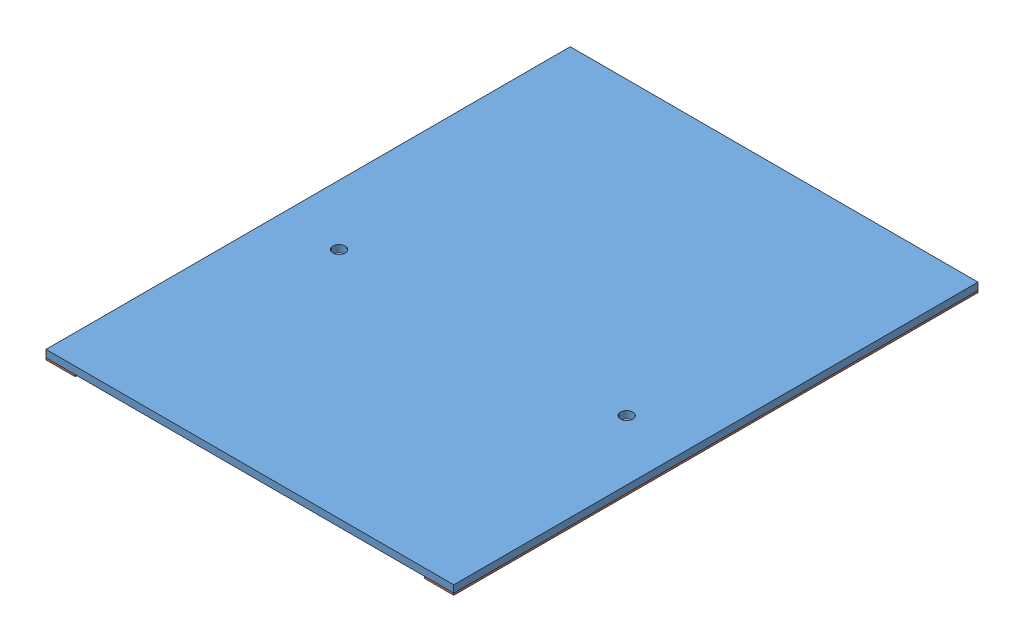
SolidWorks assembly GE-22329, configuration Default. Lengths in mm.
Overall size (355.6 7.94 457.2).
3 component instances, 2 part files, 12 mates.
Components (placement in the parent):
- GE-22328-1: GE-22328 [Default] at origin size (355.6 6.35 457.2)
- Loop_1_18-1: Loop_1_18 [Default] at (0 -1.5875 -457.2) x (0 0 1) z (-1 0 0) size (457.2 1.59 25.4)
- Loop_1_18-2: Loop_1_18 [Default] at (330.2 -1.5875 -457.2) x (0 0 1) z (-1 0 0) size (457.2 1.59 25.4)
Mates (geometry in assembly coordinates):
- Coincident1: coincident anti-aligned: plane of GE-22328-1 through (0 0 0) normal (0 -1 0); plane of Loop_1_18-1 through (0 0 -457.2) normal (0 1 0)
- Coincident2: coincident aligned: plane of GE-22328-1 through (0 6.35 0) normal (-1 0 0); plane of Loop_1_18-1 through (0 0 -457.2) normal (-1 0 0)
- Coincident3: coincident aligned: plane of GE-22328-1 through (0 6.35 0) normal (0 0 1); plane of Loop_1_18-1 through (0 0 0) normal (0 0 1)
- Coincident4: coincident anti-aligned: plane of Hook_1_18-1 through (25.4 -1.5875 0) normal (0 1 0); plane of Loop_1_18-1 through (0 -1.5875 -457.2) normal (0 -1 0)
- Coincident5: coincident aligned: plane of Hook_1_18-1 through (0 -1.5875 0) normal (-1 0 0); plane of Loop_1_18-1 through (0 0 -457.2) normal (-1 0 0)
- Coincident6: coincident aligned: plane of Hook_1_18-1 through (25.4 -1.5875 0) normal (0 0 1); plane of Loop_1_18-1 through (0 0 0) normal (0 0 1)
- Coincident7: coincident anti-aligned: plane of Hook_1_18-2 through (355.6 -1.5875 0) normal (0 1 0); plane of Loop_1_18-2 through (330.2 -1.5875 -457.2) normal (0 -1 0)
- Coincident8: coincident aligned: plane of Hook_1_18-2 through (330.2 -1.5875 0) normal (-1 0 0); plane of Loop_1_18-2 through (330.2 0 -457.2) normal (-1 0 0)
- Coincident9: coincident aligned: plane of Hook_1_18-2 through (355.6 -1.5875 0) normal (0 0 1); plane of Loop_1_18-2 through (330.2 0 0) normal (0 0 1)
- Coincident10: coincident anti-aligned: plane of GE-22328-1 through (0 0 0) normal (0 -1 0); plane of Loop_1_18-2 through (330.2 0 -457.2) normal (0 1 0)
- Coincident17: coincident aligned: plane of GE-22328-1 through (355.6 6.35 0) normal (1 0 0); plane of Loop_1_18-2 through (355.6 0 -457.2) normal (1 0 0)
- Coincident18: coincident aligned: plane of GE-22328-1 through (0 6.35 0) normal (0 0 1); plane of Loop_1_18-2 through (330.2 0 0) normal (0 0 1)
